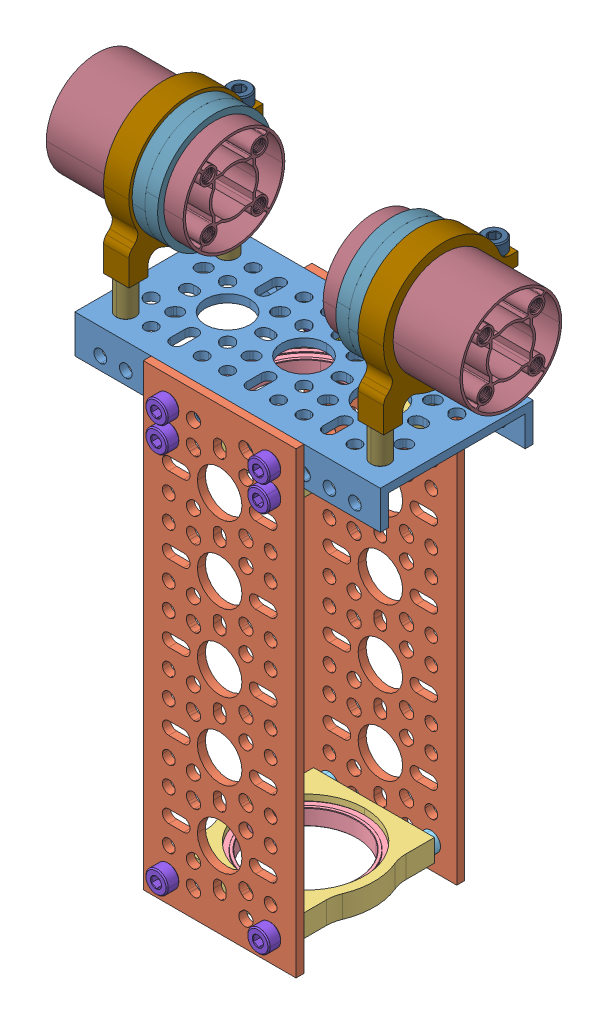
SolidWorks assembly Link1_Assembly, configuration Default. Lengths in mm.
Overall size (130 208.69 61.02).
55 component instances, 14 part files, 60 mates.
Components (placement in the parent):
- 1121-0003-0096-1: 1121-0003-0096 [Default] at (-48 -58 21.5) x (0 -1 0) z (0 0 1) size (12 96 48)
- 1123-0048-0144-1: 1123-0048-0144 [Default] at (21.5 -178 2.5) x (0 0 -1) z (1 0 0) size (2.5 144 48)
- 1123-0048-0144-2: 1123-0048-0144 [Default] at (21.5 -178 -48) x (0 0 -1) z (1 0 0) size (2.5 144 48)
- 1604-0043-0032 assembly-1: 1604-0043-0032 assembly [Default] at (22.769 -193.9479 3.755) size (56.75 7 56.75)
  - 1604-0043-0032 assembly.STEP-1: 1604-0043-0032 assembly.STEP [Default] at origin size (56.75 7 56.75)
    - 1604-0043-0032.STEP-1: 1604-0043-0032.STEP [Default] at (-22.769 20.4479 -4.255) size (43 7 43.01)
    - 1601-0039-00032.STEP-1: 1601-0039-00032.STEP [Default] at (-22.769 22.9479 -4.255) x (-0.837169 0 -0.546944) z (-0.546944 0 0.837169) size (41 5 41)
- 1604-0043-0032 assembly-2: 1604-0043-0032 assembly [Default] at (-22.769 -26.0521 3.755) x (-1 0 0) z (0 0 1) size (56.75 7 56.75)
  - 1604-0043-0032 assembly.STEP-1: 1604-0043-0032 assembly.STEP [Default] at origin size (56.75 7 56.75)
    - 1604-0043-0032.STEP-1: 1604-0043-0032.STEP [Default] at (-22.769 20.4479 -4.255) size (43 7 43.01)
    - 1601-0039-00032.STEP-1: 1601-0039-00032.STEP [Default] at (-22.769 22.9479 -4.255) x (-0.837169 0 -0.546944) z (-0.546944 0 0.837169) size (41 5 41)
- 1502-0006-0020-1: 1502-0006-0020 [Default] at (16 -170 -23) x (1 0 0) z (0 1 0) size (5.95 2 5.95)
- 1502-0006-0030-1: 1502-0006-0030 [Default] at (16 -170 22.5) x (1 0 0) z (0 -1 0) size (5.95 3 5.95)
- 1502-0006-0030-2: 1502-0006-0030 [Default] at (-16 -50 22.5) x (1 0 0) z (0 -1 0) size (5.95 3 5.95)
- 1502-0006-0030-3: 1502-0006-0030 [Default] at (16 -50 22.5) x (1 0 0) z (0 -1 0) size (5.95 3 5.95)
- 1502-0006-0030-4: 1502-0006-0030 [Default] at (-16 -170 22.5) x (1 0 0) z (0 -1 0) size (5.95 3 5.95)
- 1502-0006-0020-2: 1502-0006-0020 [Default] at (16 -50 -23) x (1 0 0) z (0 1 0) size (5.95 2 5.95)
- 1502-0006-0020-3: 1502-0006-0020 [Default] at (-16 -170 -23) x (1 0 0) z (0 1 0) size (5.95 2 5.95)
- 1502-0006-0020-4: 1502-0006-0020 [Default] at (-16 -50 -23) x (0.951063 -0.308997 0) z (0.308997 0.951063 0) size (5.95 2 5.95)
- 2803-0039-0007-2: 2803-0039-0007 [Default] at (0 -42 -18.5) x (1 0 0) z (0 1 0) size (39 3.01 7)
- 2803-0039-0007-3: 2803-0039-0007 [Default] at (0 -42 21.499) x (1 0 0) z (0 1 0) size (39 3.01 7)
- 2800-0004-0010-1: 2800-0004-0010 [Default] at (-16 -50 -16.5) size (7 7 14.01)
- 2800-0004-0010-2: 2800-0004-0010 [Default] at (16 -42 -16.5) size (7 7 14.01)
- 2800-0004-0010-3: 2800-0004-0010 [Default] at (16 -50 -16.5) x (-0.700797 -0.71336 0) z (0 0 1) size (7 7 14.01)
- 2800-0004-0010-4: 2800-0004-0010 [Default] at (-16 -42 -16.5) size (7 7 14.01)
- 2800-0004-0010-5: 2800-0004-0010 [Default] at (-16 -170 -16.5) size (7 7 14.01)
- 2800-0004-0010-6: 2800-0004-0010 [Default] at (16 -170 -16.5) size (7 7 14.01)
- 2800-0004-0010-7: 2800-0004-0010 [Default] at (16 -42 16.5) x (1 0 0) z (0 0 -1) size (7 7 14.01)
- 2800-0004-0010-8: 2800-0004-0010 [Default] at (16 -50 16.5) x (-0.700797 -0.71336 0) z (0 0 -1) size (7 7 14.01)
- 2800-0004-0010-9: 2800-0004-0010 [Default] at (-16 -50 16.5) x (1 0 0) z (0 0 -1) size (7 7 14.01)
- 2800-0004-0010-10: 2800-0004-0010 [Default] at (-16 -42 16.5) x (1 0 0) z (0 0 -1) size (7 7 14.01)
- 2800-0004-0010-11: 2800-0004-0010 [Default] at (-16 -170 16.5) x (1 0 0) z (0 0 -1) size (7 7 14.01)
- 2800-0004-0010-12: 2800-0004-0010 [Default] at (16 -170 16.5) x (1 0 0) z (0 0 -1) size (7 7 14.01)
- 1400-0032-0032 assembly-1: 1400-0032-0032 assembly [Default] at (-39.0483 -9.5558 -9.2052) x (0 0 -1) z (1 0 0) size (42.19 43 8)
  - 1400-0032-0032 assembly.STEP-1: 1400-0032-0032 assembly.STEP [Default] at origin size (42.19 43 8)
    - 1400-0032-0032.STEP-1: 1400-0032-0032.STEP [Default] at (-9.2052 9.5558 -4.9517) size (42.17 43 8)
    - 2800-0004-0012_90128A207.STEP-1: 2800-0004-0012_90128A207.STEP [Default] at (10.4635 2.5558 -0.9517) x (0.999977 0 0.006769) z (0 -1 0) size (7 7 16.01)
- 2800-0004-0018-1: 2800-0004-0018 [Default] at (-40 -18.5 -16) x (1 0 0) z (0 1 0) size (7 7 22.01)
- 2800-0004-0018-4: 2800-0004-0018 [Default] at (-40 -18.5 16) x (1 0 0) z (0 1 0) size (7 7 22.01)
- 1502-0006-0100-1: 1502-0006-0100 [Default] at (-40 -29 16) size (5.95 10 5.95)
- 1502-0006-0100-2: 1502-0006-0100 [Default] at (-40 -29 -16) size (5.95 10 5.95)
- 1400-0032-0032 assembly-3: 1400-0032-0032 assembly [Default] at (40.9517 -9.5558 -9.2052) x (0 0 -1) z (1 0 0) size (42.19 43 8)
  - 1400-0032-0032 assembly.STEP-1: 1400-0032-0032 assembly.STEP [Default] at origin size (42.19 43 8)
    - 1400-0032-0032.STEP-1: 1400-0032-0032.STEP [Default] at (-9.2052 9.5558 -4.9517) size (42.17 43 8)
    - 2800-0004-0012_90128A207.STEP-1: 2800-0004-0012_90128A207.STEP [Default] at (10.4635 2.5558 -0.9517) x (0.999977 0 0.006769) z (0 -1 0) size (7 7 16.01)
- 1502-0006-0100-3: 1502-0006-0100 [Default] at (40 -29 -16) x (-1 0 0) z (0 0 -1) size (5.95 10 5.95)
- 1502-0006-0100-4: 1502-0006-0100 [Default] at (40 -29 16) x (-1 0 0) z (0 0 -1) size (5.95 10 5.95)
- 2800-0004-0018-5: 2800-0004-0018 [Default] at (40 -18.5 -16) x (-1 0 0) z (0 1 0) size (7 7 22.01)
- 2800-0004-0018-6: 2800-0004-0018 [Default] at (40 -18.5 16) x (-1 0 0) z (0 1 0) size (7 7 22.01)
- 4103-0032-0043-1: 4103-0032-0043 [Default] at (-22 0 0) x (0 1 0) z (0 0 1) size (31.95 43 31.95)
- 4103-0032-0043-2: 4103-0032-0043 [Default] at (65 0 0) x (0 1 0) z (0 0 1) size (31.95 43 31.95)
- 1506-0032-0004-1: 1506-0032-0004 [Default] at (-36 0 0) x (0 -0.996318 -0.085736) z (0 -0.085736 0.996318) size (36 4 36)
- 1506-0032-0004-2: 1506-0032-0004 [Default] at (-32 0 0) x (0 -0.979641 0.200755) z (0 0.200755 0.979641) size (36 4 36)
- 1506-0032-0004-3: 1506-0032-0004 [Default] at (32 0 0) x (0 0.979641 -0.200755) z (0 0.200755 0.979641) size (36 4 36)
- 1506-0032-0004-4: 1506-0032-0004 [Default] at (36 0 0) x (0 0.996318 0.085736) z (0 -0.085736 0.996318) size (36 4 36)
Mates (geometry in assembly coordinates):
- Symmetric1: symmetric aligned: plane of 1121-0003-0096-1 through (48 -58 21.5) normal (1 0 0); plane of 1121-0003-0096-1 through (-48 -58 21.5) normal (-1 0 0)
- Symmetric2: symmetric aligned: plane of 1121-0003-0096-1 through (48 -82 24) normal (0 0 1); plane of 1121-0003-0096-1 through (48 -36.5 -24) normal (0 0 -1)
- Distance1: distance = 34 mm: plane of assembly through (0 0 0) normal (0 1 0); plane of assembly; plane of 1121-0003-0096-1 through (48 -34 -24) normal (0 1 0)
- Coincident2: coincident anti-aligned: plane of 1121-0003-0096-1 through (48 -82 24) normal (0 0 1); plane of 1123-0048-0144-1 through (21.5 -34 24) normal (0 0 -1)
- Concentric1: concentric aligned: cylinder of 1121-0003-0096-1 through (16 -42 -24) axis (0 0 1) radius 2; cylinder of 1123-0048-0144-1 through (16 -42 16.5) axis (0 0 1) radius 2
- Concentric2: concentric aligned: cylinder of 1121-0003-0096-1 through (-16 -42 -24) axis (0 0 1) radius 2; cylinder of 1123-0048-0144-1 through (-16 -42 16.5) axis (0 0 1) radius 2
- Concentric3: concentric aligned: cylinder of 1123-0048-0144-2 through (16 -170 -34) axis (0 0 1) radius 2; circle of 1604-0043-0032 assembly-1/1604-0043-0032 assembly.STEP-1/1604-0043-0032.STEP-1
- Coincident3: coincident aligned: cylinder of 1123-0048-0144-2 through (-16 -170 -34) axis (0 0 1) radius 2; circle of 1604-0043-0032 assembly-1/1604-0043-0032 assembly.STEP-1/1604-0043-0032.STEP-1
- Concentric4: concentric anti-aligned: cylinder of 1604-0043-0032 assembly-1/1604-0043-0032 assembly.STEP-1/1601-0039-00032.STEP-1 through (0 -173.5 -0.5) axis (0 1 0) radius 16; cylinder of 1604-0043-0032 assembly-2/1604-0043-0032 assembly.STEP-1/1601-0039-00032.STEP-1 through (0 -46.5 -0.5) axis (0 -1 0) radius 16
- Coincident4: coincident aligned: cylinder of 1123-0048-0144-2 through (16 -50 -34) axis (0 0 1) radius 2; circle of 1604-0043-0032 assembly-2/1604-0043-0032 assembly.STEP-1/1604-0043-0032.STEP-1
- Coincident5: coincident aligned: plane of 1502-0006-0020-1 through (16 -170 -24) normal (0 0 -1); plane of 1502-0006-0020-2 through (16 -50 -24) normal (0 0 -1)
- Coincident6: coincident aligned: plane of 1502-0006-0020-2 through (16 -50 -24) normal (0 0 -1); plane of 1502-0006-0020-3 through (-16 -170 -24) normal (0 0 -1)
- Coincident7: coincident aligned: plane of 1502-0006-0020-3 through (-16 -170 -24) normal (0 0 -1); plane of 1502-0006-0020-4 through (-16 -50 -24) normal (0 0 -1)
- Coincident8: coincident anti-aligned: plane of 1123-0048-0144-2 through (-24 -34 -24) normal (0 0 1); plane of 1502-0006-0020-4 through (-16 -50 -24) normal (0 0 -1)
- Concentric6: concentric anti-aligned: cylinder of 1123-0048-0144-2 through (-16 -50 -34) axis (0 0 1) radius 2; circle of 1502-0006-0020-4
- Concentric7: concentric aligned: cylinder of 1123-0048-0144-2 through (16 -50 -34) axis (0 0 1) radius 2; cylinder of 1502-0006-0020-2 through (16 -50 -24) axis (0 0 1) radius 2.975
- Concentric8: concentric aligned: cylinder of 1123-0048-0144-2 through (-16 -170 -34) axis (0 0 1) radius 2; cylinder of 1502-0006-0020-3 through (-16 -170 -24) axis (0 0 1) radius 2.975
- Concentric9: concentric aligned: circle of 1123-0048-0144-2; cylinder of 1502-0006-0020-1 through (16 -170 -24) axis (0 0 1) radius 2.975
- Coincident9: coincident anti-aligned: plane of 1604-0043-0032 assembly-1/1604-0043-0032 assembly.STEP-1/1604-0043-0032.STEP-1 through (0 -152.1927 -22) normal (0 0 -1); plane of 1502-0006-0020-3 through (-16 -170 -22) normal (0 0 1)
- Coincident10: coincident aligned: plane of 1502-0006-0030-1 through (16 -170 24) normal (0 0 1); plane of 1502-0006-0030-4 through (-16 -170 24) normal (0 0 1)
- Coincident11: coincident aligned: plane of 1502-0006-0030-1 through (16 -170 24) normal (0 0 1); plane of 1502-0006-0030-3 through (16 -50 24) normal (0 0 1)
- Coincident12: coincident aligned: plane of 1502-0006-0030-1 through (16 -170 24) normal (0 0 1); plane of 1502-0006-0030-2 through (-16 -50 24) normal (0 0 1)
- Coincident13: coincident anti-aligned: plane of 1123-0048-0144-1 through (21.5 -34 24) normal (0 0 -1); plane of 1502-0006-0030-2 through (-16 -50 24) normal (0 0 1)
- Concentric12: concentric anti-aligned: cylinder of 1123-0048-0144-1 through (-16 -170 16.5) axis (0 0 1) radius 2; cylinder of 1502-0006-0030-4 through (-16 -170 24) axis (0 0 -1) radius 2.975
- Concentric13: concentric anti-aligned: cylinder of 1123-0048-0144-1 through (16 -170 16.5) axis (0 0 1) radius 2; cylinder of 1502-0006-0030-1 through (16 -170 24) axis (0 0 -1) radius 2.975
- Concentric14: concentric anti-aligned: cylinder of 1123-0048-0144-1 through (-16 -50 16.5) axis (0 0 1) radius 2; cylinder of 1502-0006-0030-2 through (-16 -50 24) axis (0 0 -1) radius 2.975
- Concentric15: concentric anti-aligned: cylinder of 1123-0048-0144-1 through (16 -50 16.5) axis (0 0 1) radius 2; cylinder of 1502-0006-0030-3 through (16 -50 24) axis (0 0 -1) radius 2.975
- Coincident14: coincident anti-aligned: plane of 1121-0003-0096-1 through (-57.8234 -46 -21.5) normal (0 0 1); plane of 2803-0039-0007-2 through (0 -42 -21.5) normal (0 0 -1)
- Coincident15: coincident aligned: cylinder of 1121-0003-0096-1 through (-16 -42 -24) axis (0 0 1) radius 2; circle of 2803-0039-0007-2
- Coincident16: coincident anti-aligned: cylinder of 1123-0048-0144-2 through (16 -42 -34) axis (0 0 1) radius 2; circle of 2803-0039-0007-2
- Coincident17: coincident aligned: plane of 2800-0004-0010-1 through (-16 -50 -26.5) normal (0 0 1); plane of 2800-0004-0010-2 through (16 -42 -26.5) normal (0 0 1)
- Coincident18: coincident aligned: plane of 2800-0004-0010-2 through (16 -42 -26.5) normal (0 0 1); plane of 2800-0004-0010-3 through (16 -50 -26.5) normal (0 0 1)
- Coincident19: coincident aligned: plane of 2800-0004-0010-3 through (16 -50 -26.5) normal (0 0 1); plane of 2800-0004-0010-4 through (-16 -42 -26.5) normal (0 0 1)
- Coincident20: coincident anti-aligned: plane of 1123-0048-0144-2 through (21.5 -34 -26.5) normal (0 0 -1); plane of 2800-0004-0010-4 through (-16 -42 -26.5) normal (0 0 1)
- Concentric16: concentric aligned: cylinder of 1123-0048-0144-2 through (-16 -42 -34) axis (0 0 1) radius 2; cylinder of 2800-0004-0010-4 through (-16 -42 -30.5) axis (0 0 1) radius 3.5
- Concentric17: concentric aligned: cylinder of 1123-0048-0144-2 through (16 -42 -34) axis (0 0 1) radius 2; cylinder of 2800-0004-0010-2 through (16 -42 -30.5) axis (0 0 1) radius 3.5
- Concentric18: concentric aligned: cylinder of 1123-0048-0144-2 through (16 -50 -34) axis (0 0 1) radius 2; cylinder of 2800-0004-0010-3 through (16 -50 -30.5) axis (0 0 1) radius 3.5
- Concentric19: concentric aligned: cylinder of 1123-0048-0144-2 through (-16 -50 -34) axis (0 0 1) radius 2; cylinder of 2800-0004-0010-1 through (-16 -50 -30.5) axis (0 0 1) radius 3.5
- Coincident21: coincident aligned: plane of 2800-0004-0010-5 through (-16 -170 -30.5) normal (0 0 -1); plane of 2800-0004-0010-6 through (16 -170 -30.5) normal (0 0 -1)
- Coincident22: coincident anti-aligned: plane of 1123-0048-0144-2 through (21.5 -34 -26.5) normal (0 0 -1); plane of 2800-0004-0010-5 through (-16 -170 -26.5) normal (0 0 1)
- Concentric20: concentric aligned: circle of 1502-0006-0020-3; cylinder of 2800-0004-0010-5 through (-16 -170 -30.5) axis (0 0 1) radius 3.5
- Concentric21: concentric aligned: circle of 1123-0048-0144-2; cylinder of 2800-0004-0010-6 through (16 -170 -30.5) axis (0 0 1) radius 3.5
- Coincident26: coincident anti-aligned: plane of 1121-0003-0096-1 through (48 -36.5 21.5) normal (0 -1 0); plane of 2800-0004-0018-4 through (-40 -36.5 16) normal (0 1 0)
- Coincident27: coincident aligned: plane of 2800-0004-0018-1 through (-40 -36.5 -16) normal (0 1 0); plane of 2800-0004-0018-4 through (-40 -36.5 16) normal (0 1 0)
- Coincident28: coincident aligned: plane of 1502-0006-0100-1 through (-40 -24 16) normal (0 1 0); plane of 1502-0006-0100-2 through (-40 -24 -16) normal (0 1 0)
- Coincident29: coincident anti-aligned: plane of 1121-0003-0096-1 through (48 -34 -24) normal (0 1 0); plane of 1502-0006-0100-1 through (-40 -34 16) normal (0 -1 0)
- Concentric23: concentric anti-aligned: cylinder of 2800-0004-0018-4 through (-40 -40.5 16) axis (0 1 0) radius 3.5; cylinder of 1502-0006-0100-1 through (-40 -24 16) axis (0 -1 0) radius 2.975
- Concentric24: concentric anti-aligned: cylinder of 2800-0004-0018-1 through (-40 -40.5 -16) axis (0 1 0) radius 3.5; cylinder of 1502-0006-0100-2 through (-40 -24 -16) axis (0 -1 0) radius 2.975
- Coincident30: coincident anti-aligned: plane of 1400-0032-0032 assembly-1/1400-0032-0032 assembly.STEP-1/1400-0032-0032.STEP-1 through (-36 -24 13) normal (0 -1 0); plane of 1502-0006-0100-1 through (-40 -24 16) normal (0 1 0)
- Concentric25: concentric anti-aligned: circle of 1400-0032-0032 assembly-1/1400-0032-0032 assembly.STEP-1/1400-0032-0032.STEP-1; cylinder of 1502-0006-0100-1 through (-40 -24 16) axis (0 -1 0) radius 2.975
- Concentric26: concentric anti-aligned: circle of 1400-0032-0032 assembly-1/1400-0032-0032 assembly.STEP-1/1400-0032-0032.STEP-1; cylinder of 1502-0006-0100-2 through (-40 -24 -16) axis (0 -1 0) radius 2.975
- Concentric27: concentric anti-aligned: cylinder of 1121-0003-0096-1 through (-40 -44 16) axis (0 1 0) radius 2; cylinder of 1502-0006-0100-1 through (-40 -24 16) axis (0 -1 0) radius 2.975
- Concentric28: concentric anti-aligned: cylinder of 1121-0003-0096-1 through (-40 -44 -16) axis (0 1 0) radius 2; cylinder of 1502-0006-0100-2 through (-40 -24 -16) axis (0 -1 0) radius 2.975
- Concentric29: concentric anti-aligned: cylinder of 1400-0032-0032 assembly-1/1400-0032-0032 assembly.STEP-1/1400-0032-0032.STEP-1 through (-36 0 0) axis (-1 0 0) radius 16; cylinder of 4103-0032-0043-1 through (-65 0 0) axis (1 0 0) radius 15.975
- Parallel1: parallel aligned: plane of 4103-0032-0043-1 through (-22 0 0) normal (0 1 0)
- Distance2: distance = 22 mm: plane of assembly through (0 0 0) normal (1 0 0); plane of assembly; plane of 4103-0032-0043-1 through (-22 0 0) normal (1 0 0)
- Concentric30: concentric anti-aligned: cylinder of 4103-0032-0043-1 through (-65 0 0) axis (1 0 0) radius 15.975; cylinder of 1506-0032-0004-2 through (-28 0 0) axis (-1 0 0) radius 18
- Concentric31: concentric anti-aligned: cylinder of 4103-0032-0043-1 through (-65 0 0) axis (1 0 0) radius 15.975; cylinder of 1506-0032-0004-1 through (-32 0 0) axis (-1 0 0) radius 18
- Coincident33: coincident anti-aligned: plane of 1400-0032-0032 assembly-1/1400-0032-0032 assembly.STEP-1/1400-0032-0032.STEP-1 through (-36 0 0) normal (1 0 0); plane of 1506-0032-0004-1 through (-36 0 0) normal (-1 0 0)
- Coincident34: coincident anti-aligned: plane of 1506-0032-0004-1 through (-32 0 0) normal (1 0 0); plane of 1506-0032-0004-2 through (-32 0 0) normal (-1 0 0)
